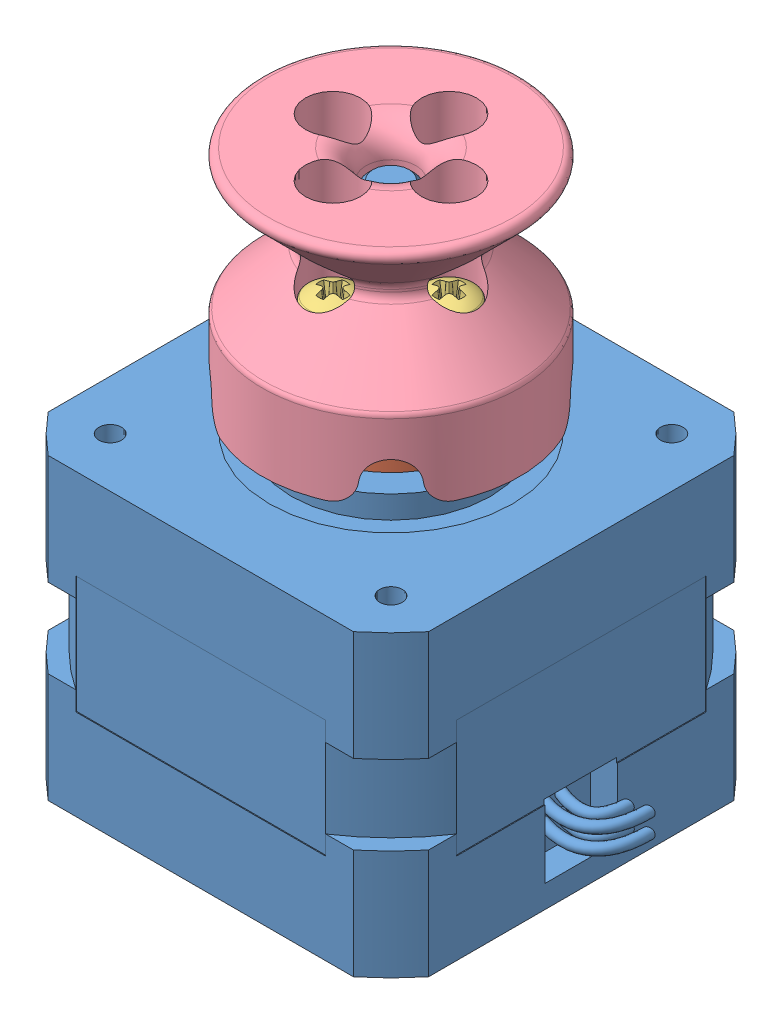
SolidWorks assembly StepperAssem_V2, configuration Default. Lengths in mm.
Overall size (46.31 60.38 42).
7 component instances, 4 part files, 21 mates.
Components (placement in the parent):
- Sparkfun_StepperMotor_09238-1: Sparkfun_StepperMotor_09238 [Default] at origin size (46.31 57.25 42)
- Sparkfun_UniversalMountingHub_10006-1: Sparkfun_UniversalMountingHub_10006 [Default] at (0 36.016 0) size (19.05 5.08 19.05)
- Sparkfun_SocketHeadMachineScrew_4-40_12-1: Sparkfun_SocketHeadMachineScrew_4-40_12 [91772A110] at (0 35.508 6.4131) x (-1 0 0) z (0 1 0) size (5.56 5.56 14.77)
- Sparkfun_SocketHeadMachineScrew_4-40_12-2: Sparkfun_SocketHeadMachineScrew_4-40_12 [91772A110] at (-6.4131 35.508 0) x (0 0 -1) z (0 1 0) size (5.56 5.56 14.77)
- Sparkfun_SocketHeadMachineScrew_4-40_12-3: Sparkfun_SocketHeadMachineScrew_4-40_12 [91772A110] at (0 35.508 -6.4131) x (1 0 0) z (0 1 0) size (5.56 5.56 14.77)
- Sparkfun_SocketHeadMachineScrew_4-40_12-4: Sparkfun_SocketHeadMachineScrew_4-40_12 [91772A110] at (6.4131 35.508 0) x (0 0 1) z (0 1 0) size (5.56 5.56 14.77)
- StepperPulley_V2-1: StepperPulley_V2 [Default] at (0 36.016 0) x (-1 0 0) z (0 -1 0) size (28.45 28.45 24.56)
Mates (geometry in assembly coordinates):
- Concentric1: concentric aligned: cylinder of Sparkfun_StepperMotor_09238-1 through (0 57.25 0) axis (0 -1 0) radius 2.5; cylinder of Sparkfun_UniversalMountingHub_10006-1 through (0 41.096 0) axis (0 -1 0) radius 2.5
- Parallel2: parallel aligned: plane of Sparkfun_StepperMotor_09238-1 through (0 0 0) normal (0 0 1); plane of Sparkfun_UniversalMountingHub_10006-1 through (0 36.016 0) normal (0 0 1)
- InPlace1: in place: plane of ? through (-54.3255 37.979 -6.4441) normal (0 1 0); plane of ? through (0 37.979 0) normal (0 1 0); moOrthogonalPlaneRef_w of ? through (-54.3255 37.979 -6.4441) normal (0 1 0); plane of ? through (0 37.979 0) normal (0 0 -1); plane of ? through (-54.3255 37.979 -6.4441) normal (0 1 0); plane of ? through (0 37.979 0) normal (1 0 0); plane of Sparkfun_UniversalMountingHub_10006-1 through (0 41.096 0) normal (0 1 0); unknown of ?
- Coincident3: coincident aligned: plane of Sparkfun_UniversalMountingHub_10006-1; plane of ?
- Coincident4: coincident aligned: moOrthogonalPlaneRef_w of Sparkfun_UniversalMountingHub_10006-1 through (0 41.096 0) normal (0 0 -1); plane of StepperPulley-1 through (0 49.63 0) normal (0 0 -1)
- Coincident5: coincident anti-aligned: moOrthogonalPlaneRef_w of Sparkfun_UniversalMountingHub_10006-1 through (0 41.096 0) normal (-1 0 0); plane of StepperPulley-1 through (0 49.63 0) normal (1 0 0)
- Parallel3: parallel anti-aligned: plane of Sparkfun_SocketHeadMachineScrew_4-40_12-1 through (0 35.508 6.4131) normal (-1 0 0)
- Coincident7: coincident aligned: plane of Sparkfun_StepperMotor_09238-1 through (0 0 0) normal (0 0 1)
- Coincident8: coincident aligned: plane of Sparkfun_StepperMotor_09238-1 through (0 0 0) normal (0 1 0)
- Coincident9: coincident aligned: plane of Sparkfun_StepperMotor_09238-1 through (0 0 0) normal (1 0 0)
- Coincident10: coincident aligned: plane of Sparkfun_StepperMotor_09238-1 through (0 57.25 0) normal (0 1 0); plane of StepperPulley-1 through (0 57.25 -6.4131) normal (0 1 0)
- Coincident11: coincident anti-aligned: plane of Sparkfun_PanHeadMachineScrew_4-40_14-1 through (4.6796 52.17 4.6796) normal (0.707107 0 -0.707107)
- Coincident12: coincident aligned: plane of Sparkfun_PanHeadMachineScrew_4-40_14-1 through (4.6796 52.17 4.6796) normal (0 1 0)
- Coincident14: coincident: cylinder of StepperPulley-1 through (0 44.55 0) axis (0 -1 0) radius 15; point of Sparkfun_PanHeadMachineScrew_4-40_14-1
- Concentric2: concentric anti-aligned: cylinder of Sparkfun_UniversalMountingHub_10006-1 through (0 41.096 6.4131) axis (0 1 0) radius 1.1303; cylinder of Sparkfun_SocketHeadMachineScrew_4-40_12-1 through (0 35.508 6.4131) axis (0 -1 0) radius 2.7813
- InPlace2: in place: plane of ? through (0 37.54 0) normal (0 -1 0); plane of ? through (0 37.54 0) normal (0 -1 0); plane of ? through (0 37.54 0) normal (0 -1 0); plane of ? through (0 37.54 0) normal (0 0 -1); plane of ? through (0 37.54 0) normal (0 -1 0); plane of ? through (0 37.54 0) normal (-1 0 0); plane of Sparkfun_UniversalMountingHub_10006-1 through (0 36.016 0) normal (0 -1 0); unknown of StepperPulley_V2-1
- Coincident15: coincident aligned: plane of Sparkfun_UniversalMountingHub_10006-1; plane of StepperPulley_V2-1
- Coincident16: coincident aligned: moOrthogonalPlaneRef_w of Sparkfun_UniversalMountingHub_10006-1 through (0 36.016 0) normal (0 0 -1); plane of StepperPulley_V2-1 through (0 36.016 0) normal (0 0 -1)
- Coincident17: coincident anti-aligned: moOrthogonalPlaneRef_w of Sparkfun_UniversalMountingHub_10006-1 through (0 36.016 0) normal (1 0 0); plane of StepperPulley_V2-1 through (0 36.016 0) normal (-1 0 0)
- Distance3: distance = 0.508 mm aligned: plane of Sparkfun_UniversalMountingHub_10006-1 through (0 36.016 0) normal (0 -1 0); plane of Sparkfun_SocketHeadMachineScrew_4-40_12-1 through (0 35.508 6.4131) normal (0 -1 0)
- Distance4: distance = 0.508 mm anti-aligned: plane of Sparkfun_SocketHeadMachineScrew_4-40_12-1 through (0 35.508 6.4131) normal (0 -1 0); plane of Sparkfun_StepperMotor_09238-1 through (0 35 0) normal (0 1 0)
